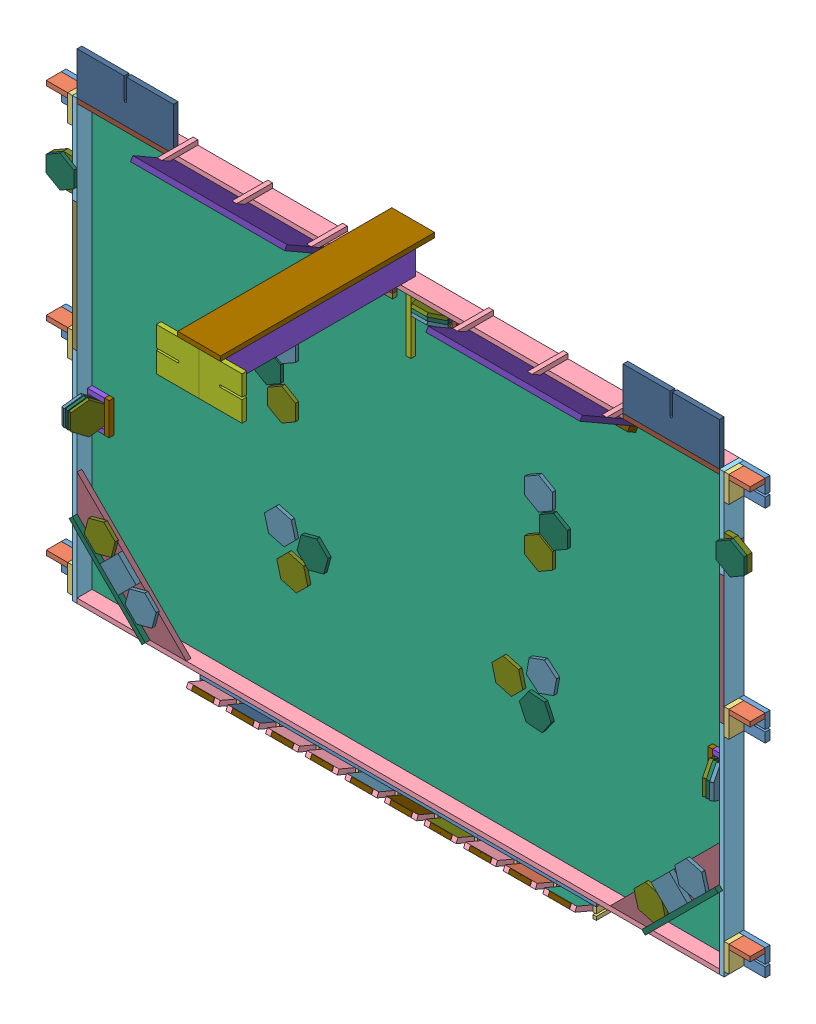
SolidWorks assembly Table_2022, configuration 預設. Lengths in mm.
Overall size (3306.25 2336 1029.4).
241 component instances, 61 part files, 0 mates.
Components (placement in the parent):
- TABLE_2021.step-1: TABLE_2021.step [預設] at origin size (3306.25 2336 1029.4)
  - BaseTable.step-1: BaseTable.step [預設] at (0 0 -22) x (1 0 0) z (0 -1 0) size (3288 1022 2266)
    - Edge Beacon Right.step-1: Edge Beacon Right.step [預設] at (-884.0915 354.4211 0) x (1 0 0) z (0 1 0) size (122 122 92)
      - EdgeBeacons_Base.step-1: EdgeBeacons_Base.step [預設] at (3967.0915 -989 -332.4211) x (0 -1 0) z (1 0 0) size (122 22 122)
      - EdgeBeacons_SmallBorder.step-1: EdgeBeacons_SmallBorder.step [預設] at (4028.0915 -950 -332.4211) x (0 1 0) z (1 0 0) size (22 70 100)
      - EdgeBeacons_LargeBorder.step-1: EdgeBeacons_LargeBorder.step [預設] at (3906.0915 -1050 -332.4211) x (1 0 0) z (0 -1 0) size (22 70 122)
    - Edge Beacon Left.step-1: Edge Beacon Left.step [預設] at (-1609.4995 44.4467 0) x (1 0 0) z (0 1 0) size (122 122 92)
      - EdgeBeacons_Base.step-1: EdgeBeacons_Base.step [預設] at (1526.4995 -39 -44.4467) x (0 -1 0) z (-1 0 0) size (122 22 122)
      - EdgeBeacons_LargeBorder.step-1: EdgeBeacons_LargeBorder.step [預設] at (1565.4995 -100 -22.4467) x (1 0 0) z (0 -1 0) size (22 70 122)
      - EdgeBeacons_SmallBorder.step-1: EdgeBeacons_SmallBorder.step [預設] at (1465.4995 22 -22.4467) x (0 -1 0) z (-1 0 0) size (22 70 100)
    - Edge Beacon Right_1.step-1: Edge Beacon Right_1.step [預設] at (-884.0915 354.4211 0) x (1 0 0) z (0 1 0) size (122 122 92)
      - EdgeBeacons_Base.step-1: EdgeBeacons_Base.step [預設] at (3967.0915 -39 -332.4211) x (0 -1 0) z (1 0 0) size (122 22 122)
      - EdgeBeacons_SmallBorder.step-1: EdgeBeacons_SmallBorder.step [預設] at (4028.0915 0 -332.4211) x (0 1 0) z (1 0 0) size (22 70 100)
      - EdgeBeacons_LargeBorder.step-1: EdgeBeacons_LargeBorder.step [預設] at (3906.0915 -100 -332.4211) x (1 0 0) z (0 -1 0) size (22 70 122)
    - Edge Beacon Right_2.step-1: Edge Beacon Right_2.step [預設] at (-1546.4323 1056.5508 0) x (1 0 0) z (0 1 0) size (122 122 92)
      - EdgeBeacons_Base.step-1: EdgeBeacons_Base.step [預設] at (4629.4323 -1939 -1034.5508) x (0 -1 0) z (1 0 0) size (122 22 122)
      - EdgeBeacons_SmallBorder.step-1: EdgeBeacons_SmallBorder.step [預設] at (4690.4323 -1900 -1034.5508) x (0 1 0) z (1 0 0) size (22 70 100)
      - EdgeBeacons_LargeBorder.step-1: EdgeBeacons_LargeBorder.step [預設] at (4568.4323 -2000 -1034.5508) x (1 0 0) z (0 -1 0) size (22 70 122)
    - Edge Beacon Left_1.step-1: Edge Beacon Left_1.step [預設] at (-933.7648 1396.3534 0) x (1 0 0) z (0 1 0) size (122 122 92)
      - EdgeBeacons_Base.step-1: EdgeBeacons_Base.step [預設] at (850.7648 -1939 -1396.3534) x (0 -1 0) z (-1 0 0) size (122 22 122)
      - EdgeBeacons_LargeBorder.step-1: EdgeBeacons_LargeBorder.step [預設] at (889.7648 -2000 -1374.3534) x (1 0 0) z (0 -1 0) size (22 70 122)
      - EdgeBeacons_SmallBorder.step-1: EdgeBeacons_SmallBorder.step [預設] at (789.7648 -1878 -1374.3534) x (0 -1 0) z (-1 0 0) size (22 70 100)
    - Edge Beacon Left_2.step-1: Edge Beacon Left_2.step [預設] at (-2304.4911 1279.1137 0) x (1 0 0) z (0 1 0) size (122 122 92)
      - EdgeBeacons_Base.step-1: EdgeBeacons_Base.step [預設] at (2221.4911 -989 -1279.1137) x (0 -1 0) z (-1 0 0) size (122 22 122)
      - EdgeBeacons_LargeBorder.step-1: EdgeBeacons_LargeBorder.step [預設] at (2260.4911 -1050 -1257.1137) x (1 0 0) z (0 -1 0) size (22 70 122)
      - EdgeBeacons_SmallBorder.step-1: EdgeBeacons_SmallBorder.step [預設] at (2160.4911 -928 -1257.1137) x (0 -1 0) z (-1 0 0) size (22 70 100)
    - BorderLong.step-1: BorderLong.step [預設] at (0 0 -22) size (3000 92 22)
    - BorderLong.step-2: BorderLong.step [預設] at (3000 0 2022) x (-1 0 0) z (0 0 -1) size (3000 92 22)
    - BorderSmall.step-1: BorderSmall.step [預設] at (-22 0 2022) x (0 0 -1) z (1 0 0) size (2044 92 22)
    - BorderSmall.step-2: BorderSmall.step [預設] at (3022 0 -22) x (0 0 1) z (-1 0 0) size (2044 92 22)
    - Ground.step-1: Ground.step [預設] at origin size (3000 22 2000)
    - MiddleBeaconTop.step-1: MiddleBeaconTop.step [預設] at (1500 22 -122) size (400 22 200)
    - MiddleBeaconVertSupport1.step-1: MiddleBeaconVertSupport1.step [預設] at (1500 22 -22) x (0 0 1) z (-1 0 0) size (200 978 22)
    - MiddleBeaconVertSupport2.step-1: MiddleBeaconVertSupport2.step [預設] at (1600 22 -233) size (200 1000 22)
    - ExperimentZone.step-1: ExperimentZone.step [預設] at (225 92 -22) size (450 22 200)
    - ExperimentZone.step-2: ExperimentZone.step [預設] at (2775 92 -22) size (450 22 200)
    - PaintExperience.step-1: PaintExperience.step [預設] at (0 92 -22) size (450 0.1 22)
    - PaintExperience.step-2: PaintExperience.step [預設] at (2550 92 -22) size (450 0.1 22)
    - BaseTable-0.step-1: BaseTable-0.step [預設] at origin size (22 0.1 600)
    - BaseTable-1.step-1: BaseTable-1.step [預設] at origin size (22 0.1 600)
  - Echantillons.step-1: Echantillons.step [預設] at origin size (3292.15 1762.13 85)
    - EchantillonBleu.step-1: EchantillonBleu.step [預設] at (900 -555 0) x (0.5 0.866025 0) z (0 0 1) size (129.9 149.69 15)
    - EchantillonBleu.step-2: EchantillonBleu.step [預設] at (892.3031 -1292.3031 15) x (0.965926 0.258819 0) z (0 0 -1) size (129.9 149.69 15)
    - EchantillonBleu.step-3: EchantillonBleu.step [預設] at (2100 -555 0) x (0.5 0.866025 0) z (0 0 1) size (129.9 149.69 15)
    - EchantillonBleu.step-4: EchantillonBleu.step [預設] at (2113.9218 -1288.3769 15) x (0.34202 -0.939693 0) z (0 0 -1) size (129.9 149.69 15)
    - EchantillonVert.step-1: EchantillonVert.step [預設] at (2085.0581 -1446.2787 15) x (0.906308 0.422618 0) z (0 0 -1) size (129.9 149.69 15)
    - EchantillonRouge.step-1: EchantillonRouge.step [預設] at (1954.3221 -1366.4789 15) x (0.258819 0.965926 0) z (0 0 -1) size (129.9 149.69 15)
    - EchantillonVert.step-2: EchantillonVert.step [預設] at (830 -675 0) x (0.5 0.866025 0) z (0 0 1) size (129.9 149.69 15)
    - EchantillonRouge.step-2: EchantillonRouge.step [預設] at (900 -795 0) x (0.5 0.866025 0) z (0 0 1) size (129.9 149.69 15)
    - EchantillonVert.step-3: EchantillonVert.step [預設] at (2170 -675 0) x (0.5 0.866025 0) z (0 0 1) size (129.9 149.69 15)
    - EchantillonRouge.step-3: EchantillonRouge.step [預設] at (2100 -795 0) x (0.5 0.866025 0) z (0 0 1) size (129.9 149.69 15)
    - EchantillonVert.step-4: EchantillonVert.step [預設] at (1044.2641 -1329.1257 15) x (0.965926 -0.258819 0) z (0 0 -1) size (129.9 149.69 15)
    - EchantillonRouge.step-4: EchantillonRouge.step [預設] at (950 -1450 15) x (0.965926 0.258819 0) z (0 0 -1) size (129.9 149.69 15)
    - EchantillonBleu.step-5: EchantillonBleu.step [預設] at (311.5685 -1879.3503 70) x (0.258819 -0.965926 0) z (0 0 1) size (129.9 149.69 15)
    - EchantillonRouge.step-5: EchantillonRouge.step [預設] at (120.6497 -1688.4315 70) x (-0.258819 0.965926 0) z (0 0 1) size (129.9 149.69 15)
    - EchantillonBleu.step-6: EchantillonBleu.step [預設] at (2879.3503 -1688.4315 70) x (0.965926 0.258819 0) z (0 0 1) size (129.9 149.69 15)
    - EchantillonRouge.step-6: EchantillonRouge.step [預設] at (2688.4315 -1879.3503 70) x (-0.965926 -0.258819 0) z (0 0 1) size (129.9 149.69 15)
    - EchantillonVert.step-5: EchantillonVert.step [預設] at (-64.9519 -300 70) x (-0.5 0.866025 0) z (0 0 1) size (129.9 149.69 15)
    - EchantillonVert.step-6: EchantillonVert.step [預設] at (3064.9519 -300 70) size (129.9 149.69 15)
  - Frises.step-1: Frises.step [預設] at origin size (2100 194.46 292.81)
    - FriseJaune.step-1: FriseJaune.step [預設] at (810 0 0) x (0 -1 0) z (0 0 1) size (194.46 720 292.81)
      - Frise.step-1: Frise.step [預設] at origin size (194.46 720 292.81)
        - FRISE_2.step-1: FRISE_2.step [預設] at origin size (169.05 720 270.81)
        - BORDURE.step-1: BORDURE.step [預設] at origin size (41.05 720 49.11)
        - TRIANGLE_GAUCHE.step-1: TRIANGLE_GAUCHE.step [預設] at origin size (40.41 22 70)
        - TRIANGLE_DROIT.step-1: TRIANGLE_DROIT.step [預設] at origin size (40.41 22 70)
        - TRIANGLE_CENTRE.step-1: TRIANGLE_CENTRE.step [預設] at origin size (40.41 22 70)
        - TaquetArriere.step-1: TaquetArriere.step [預設] at origin size (22 22 168.21)
        - TaquetArriere.step-2: TaquetArriere.step [預設] at (0 698 0) size (22 22 168.21)
        - TaquetArriere.step-3: TaquetArriere.step [預設] at (0 349 0) size (22 22 168.21)
      - FriseJaune-2.step-1: FriseJaune-2.step [預設] at origin size (150.01 720 259.81)
    - FriseViolet.step-1: FriseViolet.step [預設] at (2190 0 0) x (0 -1 0) z (0 0 1) size (194.46 720 292.81)
      - Frise_1.step-1: Frise_1.step [預設] at origin size (194.46 720 292.81)
        - FRISE_2.step-1: FRISE_2.step [預設] at origin size (169.05 720 270.81)
        - BORDURE.step-1: BORDURE.step [預設] at origin size (41.05 720 49.11)
        - TRIANGLE_GAUCHE.step-1: TRIANGLE_GAUCHE.step [預設] at origin size (40.41 22 70)
        - TRIANGLE_DROIT.step-1: TRIANGLE_DROIT.step [預設] at origin size (40.41 22 70)
        - TRIANGLE_CENTRE.step-1: TRIANGLE_CENTRE.step [預設] at origin size (40.41 22 70)
        - TaquetArriere.step-1: TaquetArriere.step [預設] at origin size (22 22 168.21)
        - TaquetArriere.step-2: TaquetArriere.step [預設] at (0 698 0) size (22 22 168.21)
        - TaquetArriere.step-3: TaquetArriere.step [預設] at (0 349 0) size (22 22 168.21)
      - FriseViolet-3.step-1: FriseViolet-3.step [預設] at origin size (150.01 720 259.81)
  - Distributeurs.step-1: Distributeurs.step [預設] at origin size (3259.81 2051.07 183.14)
    - Distributeur 2 Side.step-1: Distributeur 2 Side.step [預設] at (11 -1250 0) x (0 1 0) z (1 0 0) size (187.35 183.14 137.52)
      - TasseauBordure.step-1: TasseauBordure.step [預設] at origin size (106 22 22)
      - TasseauCote.step-1: TasseauCote.step [預設] at (-64 0 29) size (22 22 80)
      - TasseauCote.step-2: TasseauCote.step [預設] at (64 0 29) size (22 22 80)
      - TasseauAvant.step-1: TasseauAvant.step [預設] at (0 0 80) size (150 22 22)
      - EchantillonBleu.step-1: EchantillonBleu.step [預設] at (0 59.0455 -5.9792) x (0.866025 0.454532 -0.208327) z (0 0.416655 0.909065) size (129.9 149.69 15)
      - EchantillonVert.step-1: EchantillonVert.step [預設] at (0 59.0455 10.5213) x (0.866025 0.454532 -0.208327) z (0 0.416655 0.909065) size (129.9 149.69 15)
      - EchantillonRouge.step-1: EchantillonRouge.step [預設] at (0 59.0455 27.0218) x (0.866025 0.454532 -0.208327) z (0 0.416655 0.909065) size (129.9 149.69 15)
    - Distributeur 2 Side_1.step-1: Distributeur 2 Side_1.step [預設] at (2989 -1250 0) x (0 -1 0) z (-1 0 0) size (187.35 183.14 137.52)
      - TasseauBordure.step-1: TasseauBordure.step [預設] at origin size (106 22 22)
      - TasseauCote.step-1: TasseauCote.step [預設] at (-64 0 29) size (22 22 80)
      - TasseauCote.step-2: TasseauCote.step [預設] at (64 0 29) size (22 22 80)
      - TasseauAvant.step-1: TasseauAvant.step [預設] at (0 0 80) size (150 22 22)
      - EchantillonBleu.step-1: EchantillonBleu.step [預設] at (0 59.0455 -5.9792) x (0.866025 0.454532 -0.208327) z (0 0.416655 0.909065) size (129.9 149.69 15)
      - EchantillonVert.step-1: EchantillonVert.step [預設] at (0 59.0455 10.5213) x (0.866025 0.454532 -0.208327) z (0 0.416655 0.909065) size (129.9 149.69 15)
      - EchantillonRouge.step-1: EchantillonRouge.step [預設] at (0 59.0455 27.0218) x (0.866025 0.454532 -0.208327) z (0 0.416655 0.909065) size (129.9 149.69 15)
    - Distributeur 2 Top.step-1: Distributeur 2 Top.step [預設] at (1650 -11 0) x (1 0 0) z (0 -1 0) size (187.35 183.14 137.52)
      - TasseauBordure_1.step-1: TasseauBordure_1.step [預設] at origin size (106 22 22)
      - TasseauCote_1.step-1: TasseauCote_1.step [預設] at (-64 0 29) size (22 22 80)
      - TasseauCote_1.step-2: TasseauCote_1.step [預設] at (64 0 29) size (22 22 80)
      - TasseauAvant_1.step-1: TasseauAvant_1.step [預設] at (0 0 80) size (150 22 22)
      - EchantillonBleu.step-1: EchantillonBleu.step [預設] at (0 59.0455 27.0218) x (0.866025 0.454532 -0.208327) z (0 0.416655 0.909065) size (129.9 149.69 15)
      - EchantillonRouge.step-1: EchantillonRouge.step [預設] at (0 59.0455 -5.9792) x (0.866025 0.454532 -0.208327) z (0 0.416655 0.909065) size (129.9 149.69 15)
      - EchantillonVert.step-1: EchantillonVert.step [預設] at (0 59.0455 10.5213) x (0.866025 0.454532 -0.208327) z (0 0.416655 0.909065) size (129.9 149.69 15)
    - Distributeur 2 Top_1.step-1: Distributeur 2 Top_1.step [預設] at (1350 -11 0) x (1 0 0) z (0 -1 0) size (187.35 183.14 137.52)
      - TasseauBordure_1.step-1: TasseauBordure_1.step [預設] at origin size (106 22 22)
      - TasseauCote_1.step-1: TasseauCote_1.step [預設] at (-64 0 29) size (22 22 80)
      - TasseauCote_1.step-2: TasseauCote_1.step [預設] at (64 0 29) size (22 22 80)
      - TasseauAvant_1.step-1: TasseauAvant_1.step [預設] at (0 0 80) size (150 22 22)
      - EchantillonBleu.step-1: EchantillonBleu.step [預設] at (0 59.0455 27.0218) x (0.866025 0.454532 -0.208327) z (0 0.416655 0.909065) size (129.9 149.69 15)
      - EchantillonRouge.step-1: EchantillonRouge.step [預設] at (0 59.0455 -5.9792) x (0.866025 0.454532 -0.208327) z (0 0.416655 0.909065) size (129.9 149.69 15)
      - EchantillonVert.step-1: EchantillonVert.step [預設] at (0 59.0455 10.5213) x (0.866025 0.454532 -0.208327) z (0 0.416655 0.909065) size (129.9 149.69 15)
    - DistributeurCoin.step-1: DistributeurCoin.step [預設] at (0 -2000 175) size (525.56 525.56 44)
      - Taquet.step-1: Taquet.step [預設] at (0 0 -197) size (510 510 22)
      - SupportStatuette.step-1: SupportStatuette.step [預設] at (0 0 -197) size (169.71 169.71 22)
      - Taquet (1).step-1: Taquet (1).step [預設] at (0 0 -197) size (355.85 355.85 22)
    - DistributeurCoin_1.step-1: DistributeurCoin_1.step [預設] at (3000 -2000 300) x (0 1 0) z (0 0 1) size (525.56 525.56 44)
      - Taquet.step-1: Taquet.step [預設] at (0 0 -322) size (510 510 22)
      - SupportStatuette.step-1: SupportStatuette.step [預設] at (0 0 -322) size (169.71 169.71 22)
      - Taquet (1).step-1: Taquet (1).step [預設] at (0 0 -322) size (355.85 355.85 22)
    - DistributeurBordure.step-1: DistributeurBordure.step [預設] at (-200 -250 0) size (107.9 150 92)
      - Support (1).step-1: Support (1).step [預設] at (200 -50 -22) size (107.9 150 22)
      - Equerre.step-1: Equerre.step [預設] at (200 -50 -22) size (70 22 70)
    - DistributeurBordure_1.step-1: DistributeurBordure_1.step [預設] at (3250 -250 0) x (-1 0 0) z (0 0 1) size (107.9 150 92)
      - Support (1).step-1: Support (1).step [預設] at (250 50 -22) size (107.9 150 22)
      - Equerre.step-1: Equerre.step [預設] at (250 50 -22) size (70 22 70)
  - CarreFouille.step-1: CarreFouille.step [預設] at origin size (1850 85.95 153.3)
    - CarreFouilleTresorJaune.step-1: CarreFouilleTresorJaune.step [預設] at (667.5 -2000 0) x (0 -1 0) z (0 0 1) size (85.94 185 153.3)
      - CarreFouille_1.step-1: CarreFouille_1.step [預設] at (64.8942 -232.3942 0) size (85.94 185 153.3)
        - PCB_datation.step-1: PCB_datation.step [預設] at (0 0 158.7231) x (0 1 0) z (0 0 1) size (100 19.02 9.26)
          - PCB Component.step-1: PCB Component.step [預設] at (232.3942 48.7058 -10.7729) x (1 0 0) z (0 0.390731 0.920505) size (100 20 1.57)
            - Board.step-1: Board.step [預設] at origin size (100 20 1.57)
        - BASE.step-1: BASE.step [預設] at (-27.8942 232.3942 35) size (15 185 70)
        - LEFT_ARM.step-1: LEFT_ARM.step [預設] at (-27.8942 232.3942 35) size (55 15 70)
        - RIGHT_ARM.step-1: RIGHT_ARM.step [預設] at (-27.8942 232.3942 35) size (55 15 70)
        - SQUARE.step-1: SQUARE.step [預設] at (-31.092 232.3942 20.7181) x (0.920505 0 0.390731) z (-0.390731 0 0.920505) size (22 150 150)
      - CarreFouilleTresorJaune-4.step-1: CarreFouilleTresorJaune-4.step [預設] at origin size (58.62 150 138.08)
      - CarreFouilleTresorJaune-5.step-1: CarreFouilleTresorJaune-5.step [預設] at origin size (58.62 150 138.08)
    - CarreFouilleRadioactif.step-1: CarreFouilleRadioactif.step [預設] at (1037.5 -2000 0) x (0 -1 0) z (0 0 1) size (85.94 185 153.3)
      - CarreFouille_2.step-1: CarreFouille_2.step [預設] at (364.8942 -102.3942 0) size (85.94 185 153.3)
        - PCB_datation_1.step-1: PCB_datation_1.step [預設] at (0 0 158.7231) x (0 1 0) z (0 0 1) size (100 19.02 9.26)
          - PCB Component_1.step-1: PCB Component_1.step [預設] at (102.3942 348.7058 -10.7729) x (1 0 0) z (0 0.390731 0.920505) size (100 20 1.57)
            - Board.step-1: Board.step [預設] at origin size (100 20 1.57)
        - BASE.step-1: BASE.step [預設] at (-327.8942 102.3942 35) size (15 185 70)
        - LEFT_ARM.step-1: LEFT_ARM.step [預設] at (-327.8942 102.3942 35) size (55 15 70)
        - RIGHT_ARM.step-1: RIGHT_ARM.step [預設] at (-327.8942 102.3942 35) size (55 15 70)
        - SQUARE.step-1: SQUARE.step [預設] at (-331.092 102.3942 20.7181) x (0.920505 0 0.390731) z (-0.390731 0 0.920505) size (22 150 150)
      - CarreFouilleRadioactif-6.step-1: CarreFouilleRadioactif-6.step [預設] at origin size (58.62 150 138.08)
      - CarreFouilleRadioactif-7.step-1: CarreFouilleRadioactif-7.step [預設] at origin size (58.62 150 138.08)
    - CarreFouilleTresorJaune_1.step-1: CarreFouilleTresorJaune_1.step [預設] at (852.5 -2000 0) x (0 -1 0) z (0 0 1) size (85.95 185 153.3)
      - CarreFouille_3.step-1: CarreFouille_3.step [預設] at (264.8942 282.6058 0) size (85.94 185 153.3)
        - PCB_datation_2.step-1: PCB_datation_2.step [預設] at (0 0 158.7231) x (0 1 0) z (0 0 1) size (100 19.02 9.26)
          - PCB Component_2.step-1: PCB Component_2.step [預設] at (-282.6058 248.7058 -10.7729) x (1 0 0) z (0 0.390731 0.920505) size (100 20 1.57)
            - Board.step-1: Board.step [預設] at origin size (100 20 1.57)
        - BASE.step-1: BASE.step [預設] at (-227.8942 -282.6058 35) size (15 185 70)
        - LEFT_ARM.step-1: LEFT_ARM.step [預設] at (-227.8942 -282.6058 35) size (55 15 70)
        - RIGHT_ARM.step-1: RIGHT_ARM.step [預設] at (-227.8942 -282.6058 35) size (55 15 70)
        - SQUARE.step-1: SQUARE.step [預設] at (-231.092 -282.6058 20.7181) x (0.920505 0 0.390731) z (-0.390731 0 0.920505) size (22 150 150)
      - CarreFouilleTresorJaune_1-8.step-1: CarreFouilleTresorJaune_1-8.step [預設] at origin size (58.62 150 138.08)
      - CarreFouilleTresorJaune_1-9.step-1: CarreFouilleTresorJaune_1-9.step [預設] at origin size (58.62 150 138.08)
    - CarreFouilleTresorViolet.step-1: CarreFouilleTresorViolet.step [預設] at (1222.5 -2000 0) x (0 -1 0) z (0 0 1) size (85.94 185 153.3)
      - CarreFouille_4.step-1: CarreFouille_4.step [預設] at (464.8942 112.6058 0) size (85.94 185 153.3)
        - PCB_datation_3.step-1: PCB_datation_3.step [預設] at (0 0 158.7231) x (0 1 0) z (0 0 1) size (100 19.02 9.26)
          - PCB Component_3.step-1: PCB Component_3.step [預設] at (-112.6058 448.7058 -10.7729) x (1 0 0) z (0 0.390731 0.920505) size (100 20 1.57)
            - Board.step-1: Board.step [預設] at origin size (100 20 1.57)
        - BASE.step-1: BASE.step [預設] at (-427.8942 -112.6058 35) size (15 185 70)
        - LEFT_ARM.step-1: LEFT_ARM.step [預設] at (-427.8942 -112.6058 35) size (55 15 70)
        - RIGHT_ARM.step-1: RIGHT_ARM.step [預設] at (-427.8942 -112.6058 35) size (55 15 70)
        - SQUARE.step-1: SQUARE.step [預設] at (-431.092 -112.6058 20.7181) x (0.920505 0 0.390731) z (-0.390731 0 0.920505) size (22 150 150)
      - CarreFouilleTresorViolet-10.step-1: CarreFouilleTresorViolet-10.step [預設] at origin size (58.62 150 138.08)
      - CarreFouilleTresorViolet-11.step-1: CarreFouilleTresorViolet-11.step [預設] at origin size (58.62 150 138.08)
    - CarreFouilleTresorJaune_2.step-1: CarreFouilleTresorJaune_2.step [預設] at (1407.5 -2000 0) x (0 -1 0) z (0 0 1) size (85.95 185 153.3)
      - CarreFouille_5.step-1: CarreFouille_5.step [預設] at (464.8942 27.6058 0) size (85.94 185 153.3)
        - PCB_datation_4.step-1: PCB_datation_4.step [預設] at (0 0 158.7231) x (0 1 0) z (0 0 1) size (100 19.02 9.26)
          - PCB Component_4.step-1: PCB Component_4.step [預設] at (-27.6058 448.7058 -10.7729) x (1 0 0) z (0 0.390731 0.920505) size (100 20 1.57)
            - Board.step-1: Board.step [預設] at origin size (100 20 1.57)
        - BASE.step-1: BASE.step [預設] at (-427.8942 -27.6058 35) size (15 185 70)
        - LEFT_ARM.step-1: LEFT_ARM.step [預設] at (-427.8942 -27.6058 35) size (55 15 70)
        - RIGHT_ARM.step-1: RIGHT_ARM.step [預設] at (-427.8942 -27.6058 35) size (55 15 70)
        - SQUARE.step-1: SQUARE.step [預設] at (-431.092 -27.6058 20.7181) x (0.920505 0 0.390731) z (-0.390731 0 0.920505) size (22 150 150)
      - CarreFouilleTresorJaune_2-12.step-1: CarreFouilleTresorJaune_2-12.step [預設] at origin size (58.62 150 138.08)
      - CarreFouilleTresorJaune_2-13.step-1: CarreFouilleTresorJaune_2-13.step [預設] at origin size (58.62 150 138.08)
    - CarreFouilleTresorViolet_1.step-1: CarreFouilleTresorViolet_1.step [預設] at (1777.5 -2000 0) x (0 -1 0) z (0 0 1) size (85.95 185 153.3)
      - CarreFouille_6.step-1: CarreFouille_6.step [預設] at (664.8942 -42.3942 0) size (85.94 185 153.3)
        - PCB_datation_5.step-1: PCB_datation_5.step [預設] at (0 0 158.7231) x (0 1 0) z (0 0 1) size (100 19.02 9.26)
          - PCB Component_5.step-1: PCB Component_5.step [預設] at (42.3942 648.7058 -10.7729) x (1 0 0) z (0 0.390731 0.920505) size (100 20 1.57)
            - Board.step-1: Board.step [預設] at origin size (100 20 1.57)
        - BASE.step-1: BASE.step [預設] at (-627.8942 42.3942 35) size (15 185 70)
        - LEFT_ARM.step-1: LEFT_ARM.step [預設] at (-627.8942 42.3942 35) size (55 15 70)
        - RIGHT_ARM.step-1: RIGHT_ARM.step [預設] at (-627.8942 42.3942 35) size (55 15 70)
        - SQUARE.step-1: SQUARE.step [預設] at (-631.092 42.3942 20.7181) x (0.920505 0 0.390731) z (-0.390731 0 0.920505) size (22 150 150)
      - CarreFouilleTresorViolet_1-14.step-1: CarreFouilleTresorViolet_1-14.step [預設] at origin size (58.62 150 138.08)
      - CarreFouilleTresorViolet_1-15.step-1: CarreFouilleTresorViolet_1-15.step [預設] at origin size (58.62 150 138.08)
    - CarreFouilleTresorJaune_3.step-1: CarreFouilleTresorJaune_3.step [預設] at (1592.5 -2000 0) x (0 -1 0) z (0 0 1) size (85.95 185 153.3)
      - CarreFouille_7.step-1: CarreFouille_7.step [預設] at (464.8942 242.6058 0) size (85.94 185 153.3)
        - PCB_datation_6.step-1: PCB_datation_6.step [預設] at (0 0 158.7231) x (0 1 0) z (0 0 1) size (100 19.02 9.26)
          - PCB Component_6.step-1: PCB Component_6.step [預設] at (-242.6058 448.7058 -10.7729) x (1 0 0) z (0 0.390731 0.920505) size (100 20 1.57)
            - Board.step-1: Board.step [預設] at origin size (100 20 1.57)
        - BASE.step-1: BASE.step [預設] at (-427.8942 -242.6058 35) size (15 185 70)
        - LEFT_ARM.step-1: LEFT_ARM.step [預設] at (-427.8942 -242.6058 35) size (55 15 70)
        - RIGHT_ARM.step-1: RIGHT_ARM.step [預設] at (-427.8942 -242.6058 35) size (55 15 70)
        - SQUARE.step-1: SQUARE.step [預設] at (-431.092 -242.6058 20.7181) x (0.920505 0 0.390731) z (-0.390731 0 0.920505) size (22 150 150)
      - CarreFouilleTresorJaune_3-16.step-1: CarreFouilleTresorJaune_3-16.step [預設] at origin size (58.62 150 138.08)
      - CarreFouilleTresorJaune_3-17.step-1: CarreFouilleTresorJaune_3-17.step [預設] at origin size (58.62 150 138.08)
    - CarreFouilleTresorViolet_2.step-1: CarreFouilleTresorViolet_2.step [預設] at (2147.5 -2000 0) x (0 -1 0) z (0 0 1) size (85.95 185 153.3)
      - CarreFouille_8.step-1: CarreFouille_8.step [預設] at (564.8942 -12.3942 0) size (85.94 185 153.3)
        - PCB_datation_7.step-1: PCB_datation_7.step [預設] at (0 0 158.7231) x (0 1 0) z (0 0 1) size (100 19.02 9.26)
          - PCB Component_7.step-1: PCB Component_7.step [預設] at (12.3942 548.7058 -10.7729) x (1 0 0) z (0 0.390731 0.920505) size (100 20 1.57)
            - Board.step-1: Board.step [預設] at origin size (100 20 1.57)
        - BASE.step-1: BASE.step [預設] at (-527.8942 12.3942 35) size (15 185 70)
        - LEFT_ARM.step-1: LEFT_ARM.step [預設] at (-527.8942 12.3942 35) size (55 15 70)
        - RIGHT_ARM.step-1: RIGHT_ARM.step [預設] at (-527.8942 12.3942 35) size (55 15 70)
        - SQUARE.step-1: SQUARE.step [預設] at (-531.092 12.3942 20.7181) x (0.920505 0 0.390731) z (-0.390731 0 0.920505) size (22 150 150)
      - CarreFouilleTresorViolet_2-18.step-1: CarreFouilleTresorViolet_2-18.step [預設] at origin size (58.62 150 138.08)
      - CarreFouilleTresorViolet_2-19.step-1: CarreFouilleTresorViolet_2-19.step [預設] at origin size (58.62 150 138.08)
    - CarreFouilleRadioactif_1.step-1: CarreFouilleRadioactif_1.step [預設] at (1962.5 -2000 0) x (0 -1 0) z (0 0 1) size (85.95 185 153.3)
      - CarreFouille_9.step-1: CarreFouille_9.step [預設] at (564.8942 172.6058 0) size (85.94 185 153.3)
        - PCB_datation_8.step-1: PCB_datation_8.step [預設] at (0 0 158.7231) x (0 1 0) z (0 0 1) size (100 19.02 9.26)
          - PCB Component_8.step-1: PCB Component_8.step [預設] at (-172.6058 548.7058 -10.7729) x (1 0 0) z (0 0.390731 0.920505) size (100 20 1.57)
            - Board.step-1: Board.step [預設] at origin size (100 20 1.57)
        - BASE.step-1: BASE.step [預設] at (-527.8942 -172.6058 35) size (15 185 70)
        - LEFT_ARM.step-1: LEFT_ARM.step [預設] at (-527.8942 -172.6058 35) size (55 15 70)
        - RIGHT_ARM.step-1: RIGHT_ARM.step [預設] at (-527.8942 -172.6058 35) size (55 15 70)
        - SQUARE.step-1: SQUARE.step [預設] at (-531.092 -172.6058 20.7181) x (0.920505 0 0.390731) z (-0.390731 0 0.920505) size (22 150 150)
      - CarreFouilleRadioactif_1-20.step-1: CarreFouilleRadioactif_1-20.step [預設] at origin size (58.62 150 138.08)
      - CarreFouilleRadioactif_1-21.step-1: CarreFouilleRadioactif_1-21.step [預設] at origin size (58.62 150 138.08)
    - CarreFouilleTresorViolet_3.step-1: CarreFouilleTresorViolet_3.step [預設] at (2332.5 -2000 0) x (0 -1 0) z (0 0 1) size (85.95 185 153.3)
      - CarreFouille_10.step-1: CarreFouille_10.step [預設] at (564.8942 102.6058 0) size (85.94 185 153.3)
        - PCB_datation_9.step-1: PCB_datation_9.step [預設] at (0 0 158.7231) x (0 1 0) z (0 0 1) size (100 19.02 9.26)
          - PCB Component_9.step-1: PCB Component_9.step [預設] at (-102.6058 548.7058 -10.7729) x (1 0 0) z (0 0.390731 0.920505) size (100 20 1.57)
            - Board.step-1: Board.step [預設] at origin size (100 20 1.57)
        - BASE.step-1: BASE.step [預設] at (-527.8942 -102.6058 35) size (15 185 70)
        - LEFT_ARM.step-1: LEFT_ARM.step [預設] at (-527.8942 -102.6058 35) size (55 15 70)
        - RIGHT_ARM.step-1: RIGHT_ARM.step [預設] at (-527.8942 -102.6058 35) size (55 15 70)
        - SQUARE.step-1: SQUARE.step [預設] at (-531.092 -102.6058 20.7181) x (0.920505 0 0.390731) z (-0.390731 0 0.920505) size (22 150 150)
      - CarreFouilleTresorViolet_3-22.step-1: CarreFouilleTresorViolet_3-22.step [預設] at origin size (58.62 150 138.08)
      - CarreFouilleTresorViolet_3-23.step-1: CarreFouilleTresorViolet_3-23.step [預設] at origin size (58.62 150 138.08)
  - BarreSeparation.step-1: BarreSeparation.step [預設] at (1500 0 0) x (0 -1 0) z (0 0 1) size (300 22 22)
